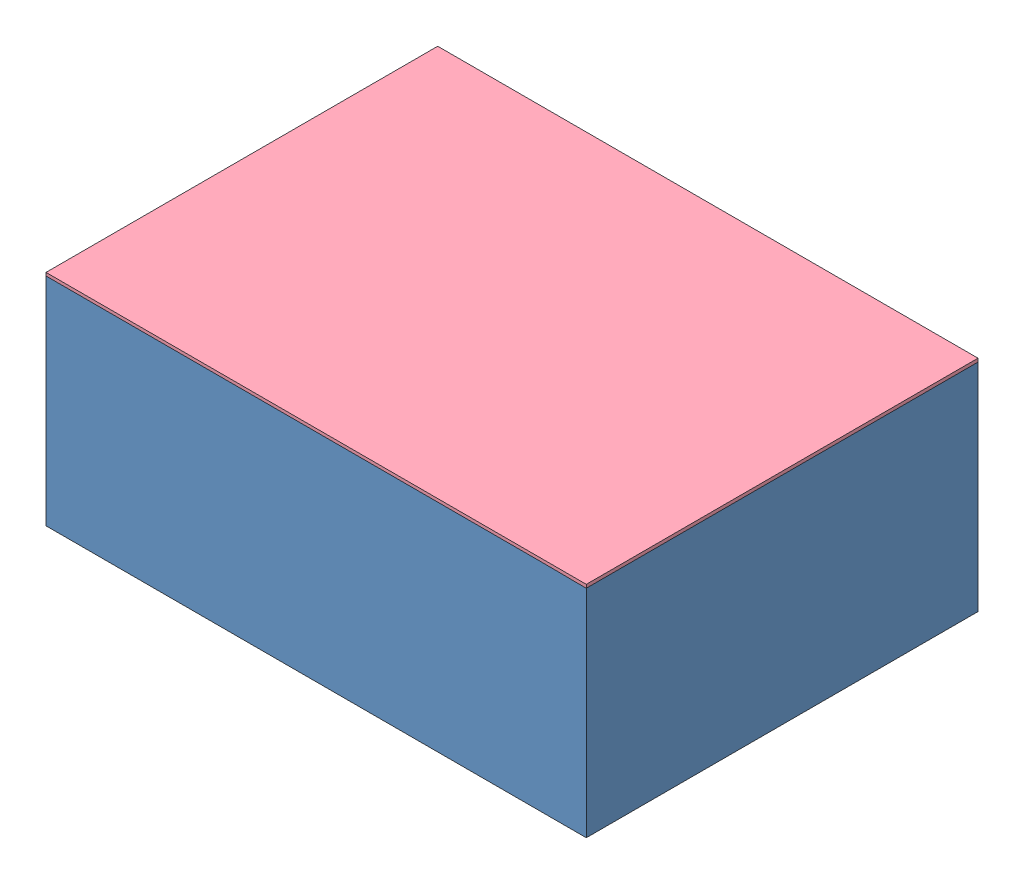
SolidWorks assembly Apoio, configuration Default. Lengths in mm.
Overall size (20 13.24 14.5).
4 component instances, 4 part files, 6 mates.
Components (placement in the parent):
- Part0-1: Part0 [Default] at (1.1547 -2.9285 1.3803) size (20 8.01 14.5)
- Part1-1: Part1 [Default] at (1.1547 0.5715 1.3803) size (8.5 9 8.5)
- Part2-1: Part2 [Default] at (1.1547 -2.1921 1.3803) x (0.890462 -0.417246 0.181614) z (-0.361298 -0.405604 0.839612) size (7.15 7.15 7.15)
- Part3-1: Part3 [Default] at (1.1547 5.0715 1.3803) size (20 0.12 14.5)
Mates (geometry in assembly coordinates):
- Concentric1: concentric: sphere of Part1-1; sphere of Part2-1
- Concentric2: concentric anti-aligned: cylinder of Part0-1 through (1.1547 5.0815 1.3803) axis (0 -1 0) radius 3.99; cylinder of Part1-1 through (1.1547 5.0715 1.3803) axis (0 1 0) radius 4
- Coincident1: coincident anti-aligned: plane of Part0-1 through (11.1547 -2.9285 -5.8697) normal (0 -1 0); plane of Part1-1 through (-3.0953 -2.9285 1.3803) normal (0 1 0)
- Distance1: distance = 0.01 mm anti-aligned: plane of Part0-1 through (11.1547 5.0815 -5.8697) normal (0 1 0); plane of Part3-1 through (11.1547 5.0715 8.6303) normal (0 -1 0)
- Coincident3: coincident aligned: plane of Part0-1 through (-8.8453 5.0815 -5.8697) normal (0 0 -1); plane of Part3-1 through (-8.8453 5.1965 -5.8697) normal (0 0 -1)
- Coincident4: coincident aligned: plane of Part0-1 through (11.1547 5.0815 8.6303) normal (1 0 0); plane of Part3-1 through (11.1547 5.1965 -5.8697) normal (1 0 0)
